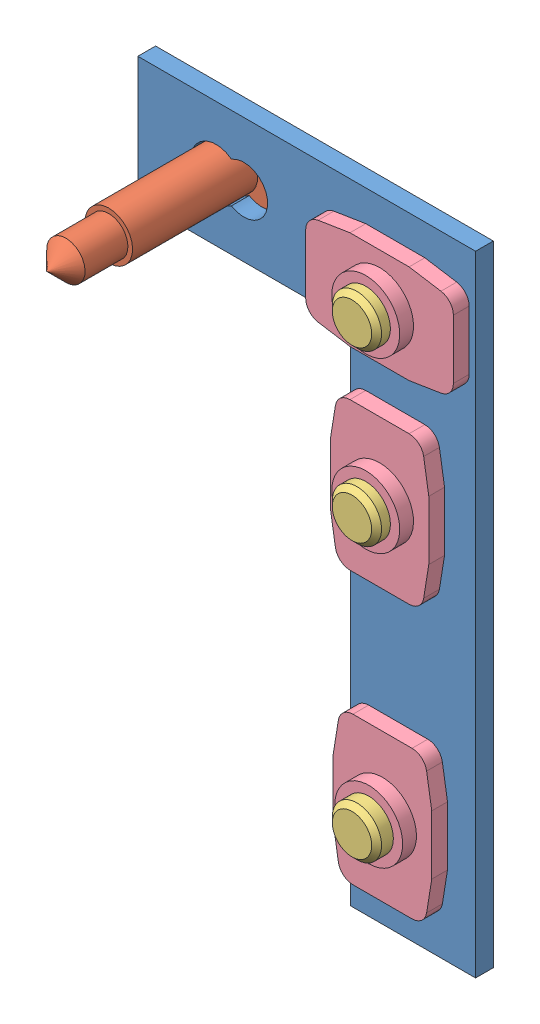
SolidWorks assembly L_BRACKET_ASSEMBLY_REVERSE, configuration Default. Lengths in mm.
Overall size (35.44 63.91 20.62).
8 component instances, 4 part files, 17 mates.
Components (placement in the parent):
- L_BRACKET-1: L_BRACKET [Default] at (11.737 31.6999 49.6565) size (34.29 63.91 1.8)
- Self Tapping Screw-1: Self Tapping Screw [Default] at (17.3402 57.3031 47.8531) x (-0.912149 0.409859 0) z (-0.409859 -0.912149 0) size (9.6 20.4 9.6)
- LP_SH_SCREW_M5_8mm-1: LP_SH_SCREW_M5_8mm [M5 x 8] at (37.3402 40.1327 55.8531) x (0 0 1) z (-0.923728 -0.383049 0) size (9.62 9 9)
- LP_SH_SCREW_M5_8mm-3: LP_SH_SCREW_M5_8mm [M5 x 8] at (37.3402 57.3031 55.8531) x (0 0 1) z (-0.923728 -0.383049 0) size (9.62 9 9)
- Tee Nut-1: Tee Nut [Default] at (37.3402 40.1327 51.4565) x (0 -1 0) z (0 0 1) size (15 10 3)
- Tee Nut-2: Tee Nut [Default] at (37.3402 57.3031 51.4565) size (15 10 3)
- Tee Nut-3: Tee Nut [Default] at (37.3402 12.3197 51.1565) x (0 1 0) z (0 0 1) size (15 10 3)
- LP_SH_SCREW_M5_8mm-4: LP_SH_SCREW_M5_8mm [M5 x 8] at (37.3402 12.3197 55.8531) x (0 0 1) z (-0.923728 -0.383049 0) size (9.62 9 9)
Mates (geometry in assembly coordinates):
- Concentric11: concentric anti-aligned: cylinder of L_BRACKET-1 through (17.3402 57.3031 49.6565) axis (0 0 1) radius 2.5798; cylinder of Self Tapping Screw-1 through (17.3402 57.3031 66.8531) axis (0 0 -1) radius 2.425
- Coincident11: coincident anti-aligned: plane of L_BRACKET-1 through (11.737 31.6999 47.8531) normal (0 0 -1); plane of Self Tapping Screw-1 through (19.5522 56.3092 47.8531) normal (0 0 1)
- Concentric10: concentric aligned: cylinder of L_BRACKET-1 through (37.3402 57.3031 49.6565) axis (0 0 1) radius 2.5798; cylinder of LP_SH_SCREW_M5_8mm-3 through (37.3402 57.3031 47.8531) axis (0 0 1) radius 2.5
- Coincident12: coincident anti-aligned: plane of L_BRACKET-1 through (11.737 31.6999 47.8531) normal (0 0 -1); plane of LP_SH_SCREW_M5_8mm-3 through (35.7462 61.1471 47.8531) normal (0 0 1)
- Concentric11: concentric aligned: cylinder of L_BRACKET-1 through (37.3402 40.1327 49.6565) axis (0 0 1) radius 2.5798; cylinder of LP_SH_SCREW_M5_8mm-1 through (37.3402 40.1327 47.8531) axis (0 0 1) radius 2.5
- Coincident13: coincident anti-aligned: plane of L_BRACKET-1 through (11.737 31.6999 47.8531) normal (0 0 -1); plane of LP_SH_SCREW_M5_8mm-1 through (35.7462 43.9767 47.8531) normal (0 0 1)
- Concentric13: concentric aligned: cylinder of L_BRACKET-1 through (37.3402 12.3197 49.6565) axis (0 0 1) radius 2.5798; cylinder of LP_SH_SCREW_M5_8mm-4 through (37.3402 12.3197 47.8531) axis (0 0 1) radius 2.5
- Coincident14: coincident anti-aligned: plane of L_BRACKET-1 through (11.737 31.6999 47.8531) normal (0 0 -1); plane of LP_SH_SCREW_M5_8mm-4 through (35.7462 16.1637 47.8531) normal (0 0 1)
- Concentric14: concentric aligned: cylinder of Tee Nut-3 through (37.3402 12.3197 54.1565) axis (0 0 1) radius 2.1; cylinder of LP_SH_SCREW_M5_8mm-4 through (37.3402 12.3197 47.8531) axis (0 0 1) radius 2.5
- Parallel4: parallel aligned: plane of L_BRACKET-1 through (43.6902 31.6999 47.8531) normal (1 0 0); plane of Tee Nut-3 through (42.3402 9.3197 52.7565) normal (1 0 0)
- Distance6: distance = 1.5 mm anti-aligned: plane of Tee Nut-3 through (34.3402 18.3197 51.1565) normal (0 0 -1); plane of L_BRACKET-1 through (11.737 31.6999 49.6565) normal (0 0 1)
- Concentric15: concentric aligned: cylinder of LP_SH_SCREW_M5_8mm-1 through (37.3402 40.1327 47.8531) axis (0 0 1) radius 2.5; cylinder of Tee Nut-1 through (37.3402 40.1327 54.4565) axis (0 0 1) radius 2.1
- Parallel5: parallel aligned: plane of L_BRACKET-1 through (43.6902 31.6999 47.8531) normal (1 0 0); plane of Tee Nut-1 through (42.3402 43.1327 53.0565) normal (1 0 0)
- Distance7: distance = 1.8 mm anti-aligned: plane of Tee Nut-1 through (40.3402 34.1327 51.4565) normal (0 0 -1); plane of L_BRACKET-1 through (11.737 31.6999 49.6565) normal (0 0 1)
- Concentric17: concentric aligned: cylinder of LP_SH_SCREW_M5_8mm-3 through (37.3402 57.3031 47.8531) axis (0 0 1) radius 2.5; cylinder of Tee Nut-2 through (37.3402 57.3031 54.4565) axis (0 0 1) radius 2.1
- Parallel6: parallel anti-aligned: plane of L_BRACKET-1 through (11.737 63.6531 47.8531) normal (0 1 0); plane of Tee Nut-2 through (34.3402 52.3031 53.0565) normal (0 -1 0)
- Distance8: distance = 1.8 mm anti-aligned: plane of Tee Nut-2 through (43.3402 60.3031 51.4565) normal (0 0 -1); plane of L_BRACKET-1 through (11.737 31.6999 49.6565) normal (0 0 1)
